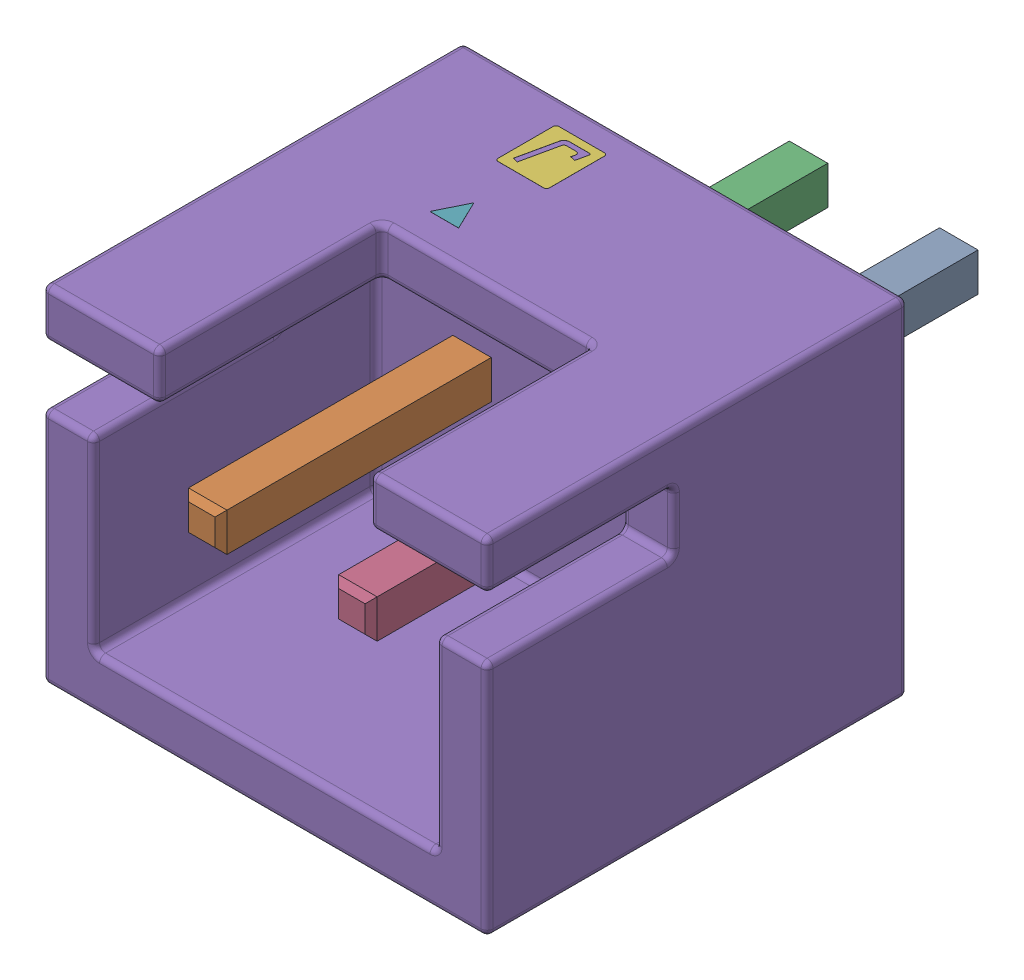
SolidWorks assembly Conn_JST_B2B-XH-A_LF_SN_eec.step, configuration Default. Lengths in mm.
Overall size (7.4 5.75 10.4).
4 component instances, 3 part files, 0 mates.
Components (placement in the parent):
- 1-0.step-1: 1-0.step [Default] at (0 0.025 0) x (-1 0 0) z (0 1 0) size (7.4 10.4 5.75)
  - 1-1.step-1: 1-1.step [Default] at origin size (3.14 10.2 0.64)
  - B2B-XH-A.step-1: B2B-XH-A.step [Default] at origin size (7.4 7 5.75)
  - JST_Logo_adjustable.step-1: JST_Logo_adjustable.step [Default] at (-1.7267 5.5034 2.841) size (0.85 2.3 0.01)
